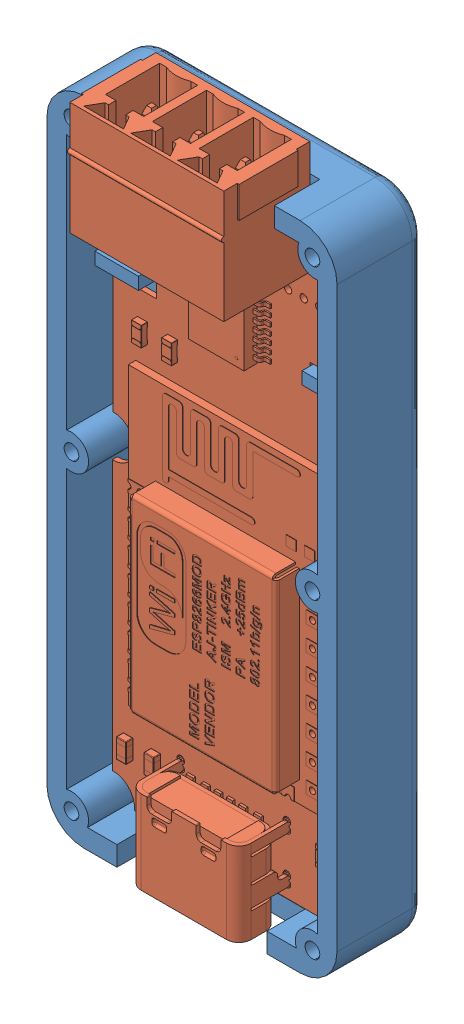
SolidWorks assembly FullHop, configuration Default. Lengths in mm.
Overall size (23.6 55.84 11.18).
3 component instances, 3 part files, 6 mates.
Components (placement in the parent):
- MatTren-1: MatTren [Default] at (49.4485 54.2144 37.6841) size (23.6 53 7.1)
- MatDuoi-1: MatDuoi [Default] at (-8.1882 54.2144 51.7838) x (-1 0 0) z (0 0 -1) size (23.6 53 9.1) (hidden)
- WLED_PCB-1: WLED_PCB [Default] at (-105.5148 -62.441 41.6604) size (19.81 55.56 10.7)
Mates (geometry in assembly coordinates):
- Coincident9: coincident aligned: plane of MatTren-1 through (8.8302 -0.3119 44.7841) normal (0 -1 0); plane of MatDuoi-1 through (32.4302 -0.3119 44.6838) normal (0 -1 0)
- Coincident10: coincident aligned: plane of MatTren-1 through (32.4302 52.6881 44.7841) normal (1 0 0); plane of MatDuoi-1 through (32.4302 52.6881 44.6838) normal (1 0 0)
- Coincident11: coincident aligned: plane of MatTren-1 through (8.8302 52.6881 44.7841) normal (-1 0 0); plane of MatDuoi-1 through (8.8302 52.6881 44.6838) normal (-1 0 0)
- Coincident12: coincident aligned: plane of MatTren-1 through (8.8302 52.6881 44.7841) normal (0 1 0); plane of MatDuoi-1 through (32.4302 52.6881 44.6838) normal (0 1 0)
- Coincident13: coincident anti-aligned: plane of MatTren-1 through (30.8302 52.6881 44.7841) normal (-1 0 0); plane of WLED_PCB-1 through (30.8302 25.091 41.2489) normal (1 0 0)
- Coincident15: coincident anti-aligned: plane of MatTren-1 through (8.8302 1.2881 44.7841) normal (0 1 0); plane of WLED_PCB-1 through (29.0422 1.2881 41.2489) normal (0 -1 0)
